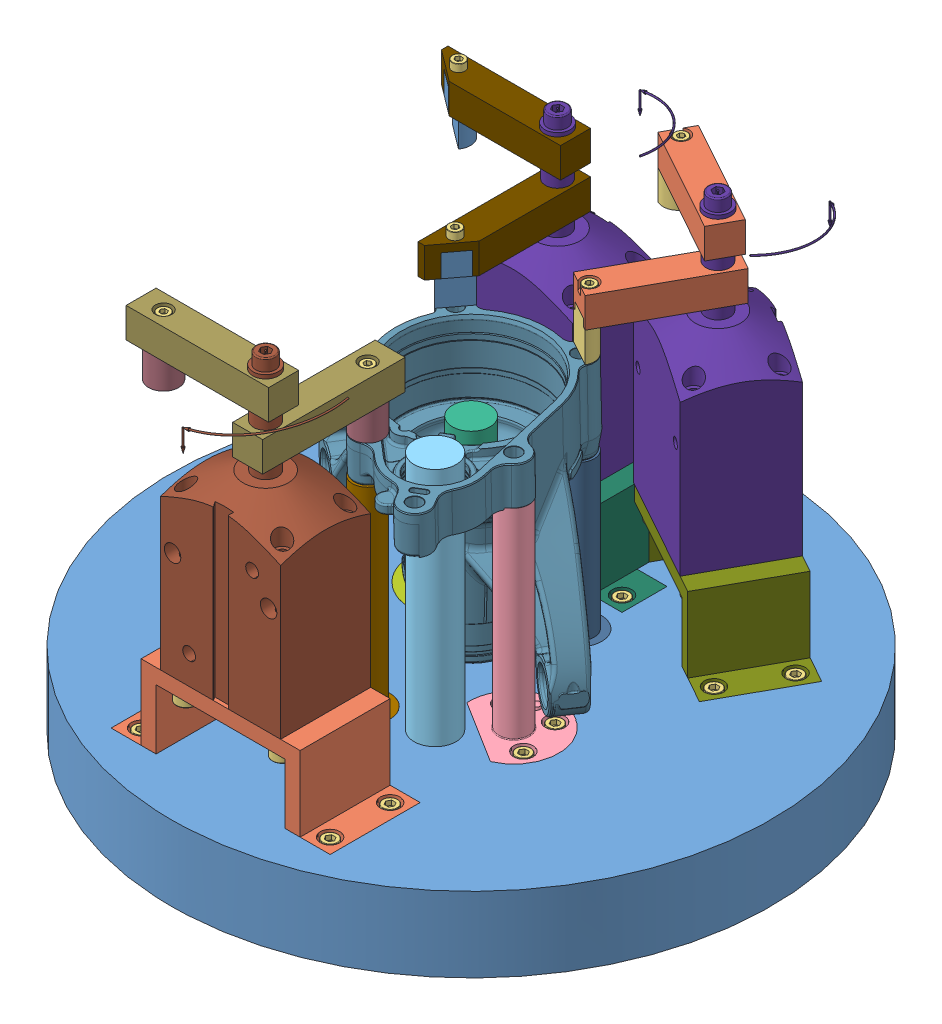
SolidWorks assembly assemb_base_31, configuration Default. Lengths in mm.
Overall size (400 290.01 400).
77 component instances, 24 part files, 96 mates.
Components (placement in the parent):
- Base_31-1: Base_31 [Default] at (159.0315 190.3727 314.3837) size (400 50 400)
- apoio_clamping_body-1: apoio_clamping_body [Default] at (159.1438 280.3727 451.4976) size (146 65 60)
- socket head cap screw_iso-1: socket head cap screw_iso [ISO 4762 M6 x 16 - 16N] at (222.1438 239.7727 431.4976) x (0 -1 0) z (0 0 1) size (22 10 10)
- socket head cap screw_iso-2: socket head cap screw_iso [ISO 4762 M6 x 16 - 16N] at (222.1438 239.7727 471.4976) x (0 -1 0) z (0 0 1) size (22 10 10)
- socket head cap screw_iso-3: socket head cap screw_iso [ISO 4762 M6 x 16 - 16N] at (96.1438 239.7727 471.4976) x (0 -1 0) z (0 0 1) size (22 10 10)
- socket head cap screw_iso-4: socket head cap screw_iso [ISO 4762 M6 x 16 - 16N] at (96.1438 239.7727 431.4976) x (0 -1 0) z (0 0 1) size (22 10 10)
- assemb_pino_posi_t1-1: assemb_pino_posi_t1 [Default] at (344.3368 218.4069 358.9702) x (-0.529295 0 0.848438) z (-0.848438 0 -0.529295) size (47 161.34 60)
  - suporte_posi_t1-1: suporte_posi_t1 [Default] at (55.5939 6.9658 111.8626) size (47 149 60)
  - pino_t1-1: pino_t1 [Default] at (55.5939 58.9658 111.8626) x (0 0 1) z (-1 0 0) size (14.5 109 14.5)
  - mola_posicionamento-1: mola_posicionamento [Default] at (55.5939 58.9658 111.8626) x (-0.837169 0 -0.546944) z (-0.546944 0 0.837169) size (14.66 52.36 14.64)
- assemb_pino_posi_t2-1: assemb_pino_posi_t2 [Default] at (29.2532 222.3882 331.9322) x (0 0 -1) z (1 0 0) size (60 130.34 60)
  - suporte_posi_t2-1: suporte_posi_t2 [Default] at (49.445 2.9845 87.4507) size (60 118 60)
  - pino_t2-1: pino_t2 [Default] at (49.445 54.9845 87.4507) size (14.5 78 14.5)
  - mola_posicionamento-1: mola_posicionamento [Default] at (49.445 54.9845 87.4507) x (-0.837169 0 -0.546944) z (-0.546944 0 0.837169) size (14.66 52.36 14.64)
- suporte_apoio_t1-1: suporte_apoio_t1 [Default] at (159.0315 225.3727 383.4976) x (0.932563 0 0.361008) z (-0.361008 0 0.932563) size (30 163.5 30)
- suporte_apoio_t2-1: suporte_apoio_t2 [Default] at (184.7261 225.3727 268.029) x (-0.000113 0 1) z (-1 0 -0.000113) size (30 133 30)
- socket head cap screw_iso-9: socket head cap screw_iso [ISO 4762 M6 x 16 - 16N] at (230.5886 239.7727 329.9611) x (0 -1 0) z (0 0 1) size (22 10 10)
- socket head cap screw_iso-11: socket head cap screw_iso [ISO 4762 M6 x 16 - 16N] at (203.0339 239.7727 336.344) x (0 -1 0) z (0 0 1) size (22 10 10)
- socket head cap screw_iso-12: socket head cap screw_iso [ISO 4762 M6 x 16 - 16N] at (136.7038 239.7727 282.4872) x (0 -1 0) z (0 0 1) size (22 10 10)
- socket head cap screw_iso-13: socket head cap screw_iso [ISO 4762 M6 x 16 - 16N] at (116.7038 239.7727 302.4872) x (0 -1 0) z (0 0 1) size (22 10 10)
- socket head cap screw_iso-14: socket head cap screw_iso [ISO 4762 M6 x 16 - 16N] at (116.7038 239.7727 262.4872) x (0 -1 0) z (0 0 1) size (22 10 10)
- socket head cap screw_iso-15: socket head cap screw_iso [ISO 4762 M6 x 16 - 16N] at (96.7038 239.7727 282.4872) x (0 -1 0) z (0 0 1) size (22 10 10)
- assemb_pneu_clamp_v3-1: assemb_pneu_clamp_v3 [Default] at (226.4561 301.3275 626.5786) x (-1 0 0) z (0 0 -1) size (138.53 190.01 139)
  - clamping_body_cw-1: clamping_body_cw [Default] at (67.3123 178.5452 175.0811) x (-1 0 0) z (0 1 0) size (95.58 86.05 190.01)
  - assemb_braco_v3-1: assemb_braco_v3 [Default] at (78.3965 110.7532 94.4609) size (95 40 21.92)
    - clamping_arm_sp_v3-1: clamping_arm_sp_v3 [Default] at (-11.0842 57.292 80.6201) x (1 0 0) z (0 1 0) size (95 20 20)
    - contact_end_full-1: contact_end_full [Default] at (56.9158 17.292 80.6201) x (0.994886 0 -0.101006) z (0.101006 0 0.994886) size (20 25 20)
    - socket head cap screw_iso-2: socket head cap screw_iso [ISO 4762 M5 x 16 - 16N] at (56.9158 56.292 80.6201) x (0 -1 0) z (0 0 1) size (21 8.5 8.5)
  - assemb_braco_v3-2: assemb_braco_v3 [Default] at (147.9324 80.7532 186.1653) x (0 0 1) z (-1 0 0) size (95 40 21.92)
    - clamping_arm_sp_v3-1: clamping_arm_sp_v3 [Default] at (-11.0842 57.292 80.6201) x (1 0 0) z (0 1 0) size (95 20 20)
    - contact_end_full-1: contact_end_full [Default] at (56.9158 17.292 80.6201) x (0.994886 0 -0.101006) z (0.101006 0 0.994886) size (20 25 20)
    - socket head cap screw_iso-2: socket head cap screw_iso [ISO 4762 M5 x 16 - 16N] at (56.9158 56.292 80.6201) x (0 -1 0) z (0 0 1) size (21 8.5 8.5)
- socket head cap screw_iso-24: socket head cap screw_iso [ISO 4762 M8 x 12 - 12N] at (191.1438 272.3727 430.4976) x (0 1 0) z (0 0 1) size (28 13 13)
- socket head cap screw_iso-25: socket head cap screw_iso [ISO 4762 M8 x 12 - 12N] at (191.1438 272.3727 472.4976) x (0 1 0) z (0 0 1) size (28 13 13)
- socket head cap screw_iso-26: socket head cap screw_iso [ISO 4762 M8 x 12 - 12N] at (127.1438 272.3727 430.4976) x (0 1 0) z (0 0 1) size (28 13 13)
- socket head cap screw_iso-27: socket head cap screw_iso [ISO 4762 M8 x 12 - 12N] at (127.1438 272.3727 472.4976) x (0 1 0) z (0 0 1) size (28 13 13)
- Peça_Cliente-1: Peça_Cliente [Default] at (159.0315 399.3727 314.3837) x (0.857167 0 -0.515038) z (0 -1 0) size (175.56 233.49 149.01)
- apoio_clamping_body_cut1-1: apoio_clamping_body_cut1 [Default] at (116.7038 280.3727 214.4872) size (146 65 60)
- apoio_clamping_body_cut2-1: apoio_clamping_body_cut2 [Default] at (217.693 280.3727 208.5548) x (0.874621 0 0.484807) z (-0.484807 0 0.874621) size (146 65 60)
- assemb_pneu_clamp_v2-2: assemb_pneu_clamp_v2 [Default] at (61.4178 300.0224 42.113) size (138.53 190.01 139)
  - clamping_body_ccw-1: clamping_body_ccw [Default] at (55.286 179.8503 172.3742) x (-1 0 0) z (0 1 0) size (95.58 86.05 190.01)
  - assemb_braco_v2-1: assemb_braco_v2 [Default] at (45.4961 98.2616 242.6188) x (-1 0 0) z (0 0 -1) size (95 45 24)
    - clamping_arm_sp_v2-1: clamping_arm_sp_v2 [Default] at (-9.7899 71.0887 70.2446) x (1 0 0) z (0 1 0) size (95 20 20)
    - contact_end_spec-1: contact_end_spec [Default] at (58.2101 31.0887 70.2446) x (0.601815 0 -0.798636) z (0.798636 0 0.601815) size (14.5 35 20)
    - socket head cap screw_iso-1: socket head cap screw_iso [ISO 4762 M5 x 12 - 12N] at (57.3074 76.0887 71.4426) x (0 -1 0) z (0 0 1) size (17 8.5 8.5)
  - assemb_braco_v2-2: assemb_braco_v2 [Default] at (125.5306 68.2616 182.1641) x (0 0 1) z (-1 0 0) size (95 45 24)
    - clamping_arm_sp_v2-1: clamping_arm_sp_v2 [Default] at (-9.7899 71.0887 70.2446) x (1 0 0) z (0 1 0) size (95 20 20)
    - contact_end_spec-1: contact_end_spec [Default] at (58.2101 31.0887 70.2446) x (0.601815 0 -0.798636) z (0.798636 0 0.601815) size (14.5 35 20)
    - socket head cap screw_iso-1: socket head cap screw_iso [ISO 4762 M5 x 12 - 12N] at (57.3074 76.0887 71.4426) x (0 -1 0) z (0 0 1) size (17 8.5 8.5)
- assemb_pneu_clamp_v1-2: assemb_pneu_clamp_v1 [Default] at (249.1962 287.189 38.6259) x (0.874621 0 0.484807) z (-0.484807 0 0.874621) size (123.53 190.01 124)
  - clamping_body_ccw-1: clamping_body_ccw [Default] at (54.8293 192.6837 163.8964) x (-1 0 0) z (0 1 0) size (95.58 86.05 190.01)
  - assemb_braco_v1-1: assemb_braco_v1 [Default] at (54.1161 128.0797 225.0616) x (-1 0 0) z (0 0 -1) size (80 40 20)
    - clamping_arm_sp_v1-2: clamping_arm_sp_v1 [Default] at (-0.7132 54.1041 61.1653) x (1 0 0) z (0 1 0) size (80 20 20)
    - contact_end_half-1: contact_end_half [Default] at (67.2868 14.1041 61.1653) size (10 25 20)
    - socket head cap screw_iso-2: socket head cap screw_iso [ISO 4762 M5 x 16 - 16N] at (62.2868 53.6041 61.1653) x (0 -1 0) z (0 0 1) size (21 8.5 8.5)
  - assemb_braco_v1-2: assemb_braco_v1 [Default] at (115.9945 98.0797 164.6096) x (0 0 1) z (-1 0 0) size (80 40 20)
    - clamping_arm_sp_v1-2: clamping_arm_sp_v1 [Default] at (-0.7132 54.1041 61.1653) x (1 0 0) z (0 1 0) size (80 20 20)
    - contact_end_half-1: contact_end_half [Default] at (67.2868 14.1041 61.1653) size (10 25 20)
    - socket head cap screw_iso-2: socket head cap screw_iso [ISO 4762 M5 x 16 - 16N] at (62.2868 53.6041 61.1653) x (0 -1 0) z (0 0 1) size (21 8.5 8.5)
- socket head cap screw_iso-36: socket head cap screw_iso [ISO 4762 M6 x 16 - 16N] at (263.098 239.7727 256.59) x (0 -1 0) z (0 0 1) size (22 10 10)
- socket head cap screw_iso-37: socket head cap screw_iso [ISO 4762 M6 x 16 - 16N] at (282.4903 239.7727 221.6052) x (0 -1 0) z (0 0 1) size (22 10 10)
- socket head cap screw_iso-38: socket head cap screw_iso [ISO 4762 M6 x 16 - 16N] at (172.288 239.7727 160.5195) x (0 -1 0) z (0 0 1) size (22 10 10)
- socket head cap screw_iso-39: socket head cap screw_iso [ISO 4762 M6 x 16 - 16N] at (53.7038 239.7727 194.4872) x (0 -1 0) z (0 0 1) size (22 10 10)
- socket head cap screw_iso-40: socket head cap screw_iso [ISO 4762 M6 x 16 - 16N] at (53.7038 239.7727 234.4872) x (0 -1 0) z (0 0 1) size (22 10 10)
- socket head cap screw_iso-41: socket head cap screw_iso [ISO 4762 M6 x 16 - 16N] at (179.7038 239.7727 234.4872) x (0 -1 0) z (0 0 1) size (22 10 10)
- socket head cap screw_iso-42: socket head cap screw_iso [ISO 4762 M8 x 12 - 12N] at (84.7038 272.3727 235.4872) x (0 1 0) z (0 0 1) size (28 13 13)
- socket head cap screw_iso-43: socket head cap screw_iso [ISO 4762 M8 x 20 - 20N] at (84.7038 272.3727 193.4872) x (0 1 0) z (0 0 1) size (28 13 13)
- socket head cap screw_iso-44: socket head cap screw_iso [ISO 4762 M8 x 12 - 12N] at (148.7038 272.3727 193.4872) x (0 1 0) z (0 0 1) size (28 13 13)
- socket head cap screw_iso-45: socket head cap screw_iso [ISO 4762 M8 x 12 - 12N] at (148.7038 272.3727 235.4872) x (0 1 0) z (0 0 1) size (28 13 13)
- socket head cap screw_iso-46: socket head cap screw_iso [ISO 4762 M8 x 12 - 12N] at (179.5242 272.3727 211.408) x (0 1 0) z (0 0 1) size (28 13 13)
- socket head cap screw_iso-47: socket head cap screw_iso [ISO 4762 M8 x 12 - 12N] at (199.886 272.3727 174.6739) x (0 1 0) z (0 0 1) size (28 13 13)
- socket head cap screw_iso-48: socket head cap screw_iso [ISO 4762 M8 x 12 - 12N] at (255.8618 272.3727 205.7015) x (0 1 0) z (0 0 1) size (28 13 13)
- socket head cap screw_iso-49: socket head cap screw_iso [ISO 4762 M8 x 12 - 12N] at (235.4999 272.3727 242.4356) x (0 1 0) z (0 0 1) size (28 13 13)
- socket head cap screw_iso-50: socket head cap screw_iso [ISO 4762 M6 x 16 - 16N] at (236.9715 239.7727 357.5158) x (0 -1 0) z (0 0 1) size (22 10 10)
- parallel pin hardened 02_iso-1: parallel pin hardened 02_iso [ISO 8735-6x28-A-St] at (215.4893 242.4727 327.4458) x (0 -1 0) z (0 0 1) size (28 6 6)
- pino_guia_t1-1: pino_guia_t1 [Default] at (195.0205 240.3727 374.3899) x (0.986605 0 -0.163126) z (0.163126 0 0.986605) size (28 180 28)
- pino_guia_t2-1: pino_guia_t2 [Default] at (159.0167 240.3727 314.3589) x (0.978415 0 0.206649) z (-0.206649 0 0.978415) size (25 153 25)
Mates (geometry in assembly coordinates):
- Concentric5: concentric aligned: cylinder of Base_31-1 through (222.1438 225.3727 471.4976) axis (0 1 0) radius 2.5; cylinder of apoio_clamping_body-1 through (222.1438 225.3727 471.4976) axis (0 1 0) radius 3.3
- Concentric6: concentric aligned: cylinder of Base_31-1 through (96.1438 225.3727 431.4976) axis (0 1 0) radius 2.5; cylinder of apoio_clamping_body-1 through (96.1438 225.3727 431.4976) axis (0 1 0) radius 3.3
- Coincident3: coincident anti-aligned: plane of Base_31-1 through (159.0315 225.3727 314.3837) normal (0 1 0); plane of apoio_clamping_body-1 through (159.1438 225.3727 451.4976) normal (0 -1 0)
- Concentric7: concentric aligned: cylinder of apoio_clamping_body-1 through (222.1438 225.3727 431.4976) axis (0 1 0) radius 3.3; cylinder of socket head cap screw_iso-1 through (222.1438 271.5227 431.4976) axis (0 1 0) radius 5
- Coincident4: coincident anti-aligned: plane of apoio_clamping_body-1 through (222.1438 233.7727 431.4976) normal (0 1 0); plane of socket head cap screw_iso-1 through (227.1438 233.7727 431.4976) normal (0 -1 0)
- Concentric8: concentric aligned: cylinder of apoio_clamping_body-1 through (222.1438 225.3727 471.4976) axis (0 1 0) radius 3.3; cylinder of socket head cap screw_iso-2 through (222.1438 271.5227 471.4976) axis (0 1 0) radius 5
- Coincident5: coincident anti-aligned: plane of apoio_clamping_body-1 through (222.1438 233.7727 471.4976) normal (0 1 0); plane of socket head cap screw_iso-2 through (227.1438 233.7727 471.4976) normal (0 -1 0)
- Concentric9: concentric aligned: cylinder of apoio_clamping_body-1 through (96.1438 225.3727 471.4976) axis (0 1 0) radius 3.3; cylinder of socket head cap screw_iso-3 through (96.1438 271.5227 471.4976) axis (0 1 0) radius 5
- Coincident6: coincident anti-aligned: plane of apoio_clamping_body-1 through (96.1438 233.7727 471.4976) normal (0 1 0); plane of socket head cap screw_iso-3 through (101.1438 233.7727 471.4976) normal (0 -1 0)
- Concentric10: concentric aligned: cylinder of apoio_clamping_body-1 through (96.1438 225.3727 431.4976) axis (0 1 0) radius 3.3; cylinder of socket head cap screw_iso-4 through (96.1438 271.5227 431.4976) axis (0 1 0) radius 5
- Coincident7: coincident anti-aligned: plane of apoio_clamping_body-1 through (96.1438 233.7727 431.4976) normal (0 1 0); plane of socket head cap screw_iso-4 through (101.1438 233.7727 431.4976) normal (0 -1 0)
- Concentric15: concentric aligned: cylinder of Base_31-1 through (203.0339 225.3727 336.344) axis (0 1 0) radius 2.5; cylinder of assemb_pino_posi_t1-1/suporte_posi_t1-1 through (203.0339 225.3727 336.344) axis (0 1 0) radius 3.2
- Coincident12: coincident anti-aligned: plane of Base_31-1 through (220.0027 225.3727 346.9299) normal (0 1 0); plane of assemb_pino_posi_t1-1/suporte_posi_t1-1 through (220.0027 225.3727 346.9299) normal (0 -1 0)
- Concentric17: concentric anti-aligned: cylinder of Base_31-1 through (116.7038 225.3727 282.4872) axis (0 1 0) radius 30; cylinder of assemb_pino_posi_t2-1/suporte_posi_t2-1 through (116.7038 240.3727 282.4872) axis (0 -1 0) radius 30
- Concentric18: concentric aligned: cylinder of Base_31-1 through (136.7038 225.3727 282.4872) axis (0 1 0) radius 2.5; cylinder of assemb_pino_posi_t2-1/suporte_posi_t2-1 through (136.7038 225.3727 282.4872) axis (0 1 0) radius 3.2
- Coincident13: coincident anti-aligned: plane of Base_31-1 through (116.7038 225.3727 282.4872) normal (0 1 0); plane of assemb_pino_posi_t2-1/suporte_posi_t2-1 through (116.7038 225.3727 282.4872) normal (0 -1 0)
- Concentric19: concentric anti-aligned: cylinder of Base_31-1 through (159.0315 225.3727 383.4976) axis (0 1 0) radius 15; cylinder of suporte_apoio_t1-1 through (159.0315 240.3727 383.4976) axis (0 -1 0) radius 15
- Coincident14: coincident anti-aligned: plane of Base_31-1 through (159.0315 225.3727 383.4976) normal (0 1 0); plane of suporte_apoio_t1-1 through (159.0315 225.3727 383.4976) normal (0 -1 0)
- Concentric20: concentric anti-aligned: cylinder of Base_31-1 through (184.7261 225.3727 268.029) axis (0 1 0) radius 15; cylinder of suporte_apoio_t2-1 through (184.7261 240.3727 268.029) axis (0 -1 0) radius 15
- Coincident15: coincident anti-aligned: plane of Base_31-1 through (184.7261 225.3727 268.029) normal (0 1 0); plane of suporte_apoio_t2-1 through (184.7261 225.3727 268.029) normal (0 -1 0)
- Concentric21: concentric aligned: cylinder of assemb_pino_posi_t1-1/suporte_posi_t1-1 through (230.5886 225.3727 329.9611) axis (0 1 0) radius 3.2; cylinder of socket head cap screw_iso-9 through (230.5886 271.5227 329.9611) axis (0 1 0) radius 5
- Coincident16: coincident anti-aligned: plane of assemb_pino_posi_t1-1/suporte_posi_t1-1 through (230.5886 233.7727 329.9611) normal (0 1 0); plane of socket head cap screw_iso-9 through (235.5886 233.7727 329.9611) normal (0 -1 0)
- Concentric23: concentric aligned: cylinder of assemb_pino_posi_t1-1/suporte_posi_t1-1 through (203.0339 225.3727 336.344) axis (0 1 0) radius 3.2; cylinder of socket head cap screw_iso-11 through (203.0339 271.5227 336.344) axis (0 1 0) radius 5
- Coincident18: coincident anti-aligned: plane of assemb_pino_posi_t1-1/suporte_posi_t1-1 through (203.0339 233.7727 336.344) normal (0 1 0); plane of socket head cap screw_iso-11 through (208.0339 233.7727 336.344) normal (0 -1 0)
- Concentric24: concentric aligned: cylinder of assemb_pino_posi_t2-1/suporte_posi_t2-1 through (136.7038 225.3727 282.4872) axis (0 1 0) radius 3.2; cylinder of socket head cap screw_iso-12 through (136.7038 271.5227 282.4872) axis (0 1 0) radius 5
- Coincident19: coincident anti-aligned: plane of assemb_pino_posi_t2-1/suporte_posi_t2-1 through (136.7038 233.7727 282.4872) normal (0 1 0); plane of socket head cap screw_iso-12 through (141.7038 233.7727 282.4872) normal (0 -1 0)
- Concentric25: concentric aligned: cylinder of assemb_pino_posi_t2-1/suporte_posi_t2-1 through (116.7038 225.3727 302.4872) axis (0 1 0) radius 3.2; cylinder of socket head cap screw_iso-13 through (116.7038 271.5227 302.4872) axis (0 1 0) radius 5
- Coincident20: coincident anti-aligned: plane of assemb_pino_posi_t2-1/suporte_posi_t2-1 through (116.7038 233.7727 302.4872) normal (0 1 0); plane of socket head cap screw_iso-13 through (121.7038 233.7727 302.4872) normal (0 -1 0)
- Concentric26: concentric aligned: cylinder of assemb_pino_posi_t2-1/suporte_posi_t2-1 through (116.7038 225.3727 262.4872) axis (0 1 0) radius 3.2; cylinder of socket head cap screw_iso-14 through (116.7038 271.5227 262.4872) axis (0 1 0) radius 5
- Coincident21: coincident anti-aligned: plane of assemb_pino_posi_t2-1/suporte_posi_t2-1 through (116.7038 233.7727 262.4872) normal (0 1 0); plane of socket head cap screw_iso-14 through (121.7038 233.7727 262.4872) normal (0 -1 0)
- Concentric27: concentric aligned: cylinder of assemb_pino_posi_t2-1/suporte_posi_t2-1 through (96.7038 225.3727 282.4872) axis (0 1 0) radius 3.2; cylinder of socket head cap screw_iso-15 through (96.7038 271.5227 282.4872) axis (0 1 0) radius 5
- Coincident22: coincident anti-aligned: plane of assemb_pino_posi_t2-1/suporte_posi_t2-1 through (96.7038 233.7727 282.4872) normal (0 1 0); plane of socket head cap screw_iso-15 through (101.7038 233.7727 282.4872) normal (0 -1 0)
- Coincident23: coincident aligned: plane of apoio_clamping_body-1 through (106.1438 290.3727 421.4976) normal (0 0 -1); plane of assemb_pneu_clamp_v3-1/clamping_body_cw-1 through (119.1438 410.8727 421.4976) normal (0 0 -1)
- Concentric28: concentric aligned: cylinder of apoio_clamping_body-1 through (191.1438 225.3727 430.4976) axis (0 1 0) radius 4.5; cylinder of assemb_pneu_clamp_v3-1/clamping_body_cw-1 through (191.1438 290.3727 430.4976) axis (0 1 0) radius 3.375
- Concentric29: concentric aligned: cylinder of apoio_clamping_body-1 through (127.1438 225.3727 472.4976) axis (0 1 0) radius 4.5; cylinder of assemb_pneu_clamp_v3-1/clamping_body_cw-1 through (127.1438 290.3727 472.4976) axis (0 1 0) radius 3.375
- Coincident25: coincident anti-aligned: plane of apoio_clamping_body-1 through (159.1438 290.3727 451.4976) normal (0 1 0); plane of assemb_pneu_clamp_v3-1/clamping_body_cw-1 through (199.1438 290.3727 481.4976) normal (0 -1 0)
- Concentric42: concentric anti-aligned: cylinder of apoio_clamping_body-1 through (191.1438 225.3727 430.4976) axis (0 1 0) radius 4.5; cylinder of socket head cap screw_iso-24 through (191.1438 240.6227 430.4976) axis (0 -1 0) radius 6.5
- Coincident36: coincident anti-aligned: plane of apoio_clamping_body-1 through (159.1438 280.3727 451.4976) normal (0 -1 0); plane of socket head cap screw_iso-24 through (184.6438 280.3727 430.4976) normal (0 1 0)
- Concentric43: concentric anti-aligned: cylinder of apoio_clamping_body-1 through (191.1438 225.3727 472.4976) axis (0 1 0) radius 4.5; cylinder of socket head cap screw_iso-25 through (191.1438 240.6227 472.4976) axis (0 -1 0) radius 6.5
- Coincident37: coincident anti-aligned: plane of apoio_clamping_body-1 through (159.1438 280.3727 451.4976) normal (0 -1 0); plane of socket head cap screw_iso-25 through (184.6438 280.3727 472.4976) normal (0 1 0)
- Concentric44: concentric anti-aligned: cylinder of apoio_clamping_body-1 through (127.1438 225.3727 430.4976) axis (0 1 0) radius 4.5; cylinder of socket head cap screw_iso-26 through (127.1438 240.6227 430.4976) axis (0 -1 0) radius 6.5
- Coincident38: coincident anti-aligned: plane of apoio_clamping_body-1 through (159.1438 280.3727 451.4976) normal (0 -1 0); plane of socket head cap screw_iso-26 through (120.6438 280.3727 430.4976) normal (0 1 0)
- Concentric45: concentric anti-aligned: cylinder of apoio_clamping_body-1 through (127.1438 225.3727 472.4976) axis (0 1 0) radius 4.5; cylinder of socket head cap screw_iso-27 through (127.1438 240.6227 472.4976) axis (0 -1 0) radius 6.5
- Coincident39: coincident anti-aligned: plane of apoio_clamping_body-1 through (159.1438 280.3727 451.4976) normal (0 -1 0); plane of socket head cap screw_iso-27 through (120.6438 280.3727 472.4976) normal (0 1 0)
- Concentric46: concentric aligned: cylinder of assemb_pino_posi_t1-1/pino_t1-1 through (220.0027 386.3727 346.9299) axis (0 1 0) radius 5; cylinder of Peça_Cliente-1 through (220.0027 369.6714 346.9299) axis (0 1 0) radius 4.75
- Concentric47: concentric aligned: cylinder of Peça_Cliente-1 through (116.7038 337.4784 282.4872) axis (0 1 0) radius 4.5; cylinder of assemb_pino_posi_t2-1/pino_t2-1 through (116.7038 355.3727 282.4872) axis (0 1 0) radius 5
- Coincident40: coincident anti-aligned: plane of assemb_pino_posi_t1-1/suporte_posi_t1-1 through (220.0027 374.3727 346.9299) normal (0 1 0); plane of Peça_Cliente-1 through (220.0027 374.3727 346.9299) normal (0 -1 0)
- Concentric48: concentric aligned: cylinder of Base_31-1 through (53.7038 225.3727 194.4872) axis (0 1 0) radius 2.5; cylinder of apoio_clamping_body_cut1-1 through (53.7038 225.3727 194.4872) axis (0 1 0) radius 3.3
- Concentric49: concentric aligned: cylinder of Base_31-1 through (179.7038 225.3727 234.4872) axis (0 1 0) radius 2.5; cylinder of apoio_clamping_body_cut1-1 through (179.7038 225.3727 234.4872) axis (0 1 0) radius 3.3
- Coincident41: coincident anti-aligned: plane of Base_31-1 through (159.0315 225.3727 314.3837) normal (0 1 0); plane of apoio_clamping_body_cut1-1 through (116.7038 225.3727 214.4872) normal (0 -1 0)
- Concentric50: concentric aligned: cylinder of Base_31-1 through (263.098 225.3727 256.59) axis (0 1 0) radius 2.5; cylinder of apoio_clamping_body_cut2-1 through (263.098 225.3727 256.59) axis (0 1 0) radius 3.3
- Concentric51: concentric aligned: cylinder of Base_31-1 through (172.288 225.3727 160.5195) axis (0 1 0) radius 2.5; cylinder of apoio_clamping_body_cut2-1 through (172.288 225.3727 160.5195) axis (0 1 0) radius 3.3
- Coincident42: coincident anti-aligned: plane of Base_31-1 through (159.0315 225.3727 314.3837) normal (0 1 0); plane of apoio_clamping_body_cut2-1 through (217.693 225.3727 208.5548) normal (0 -1 0)
- Coincident43: coincident aligned: plane of apoio_clamping_body_cut1-1 through (63.7038 290.3727 244.4872) normal (0 0 1); plane of assemb_pneu_clamp_v2-2/clamping_body_ccw-1 through (156.7038 410.8727 244.4872) normal (0 0 1)
- Concentric52: concentric aligned: cylinder of apoio_clamping_body_cut1-1 through (148.7038 225.3727 235.4872) axis (0 1 0) radius 4.5; cylinder of assemb_pneu_clamp_v2-2/clamping_body_ccw-1 through (148.7038 290.3727 235.4872) axis (0 1 0) radius 3.25
- Coincident44: coincident anti-aligned: plane of apoio_clamping_body_cut1-1 through (116.7038 290.3727 214.4872) normal (0 1 0); plane of assemb_pneu_clamp_v2-2/clamping_body_ccw-1 through (76.7038 290.3727 184.4872) normal (0 -1 0)
- Coincident45: coincident aligned: plane of apoio_clamping_body_cut2-1 through (156.7938 290.3727 209.0987) normal (-0.484807 0 0.874621); plane of assemb_pneu_clamp_v1-2/clamping_body_ccw-1 through (238.1336 410.8727 254.1857) normal (-0.484807 0 0.874621)
- Concentric53: concentric aligned: cylinder of apoio_clamping_body_cut2-1 through (235.4999 225.3727 242.4356) axis (0 1 0) radius 4.5; cylinder of assemb_pneu_clamp_v1-2/clamping_body_ccw-1 through (235.4999 290.3727 242.4356) axis (0 1 0) radius 3.25
- Coincident46: coincident anti-aligned: plane of apoio_clamping_body_cut2-1 through (217.693 290.3727 208.5548) normal (0 1 0); plane of assemb_pneu_clamp_v1-2/clamping_body_ccw-1 through (197.2523 290.3727 162.9239) normal (0 -1 0)
- Concentric62: concentric aligned: cylinder of apoio_clamping_body_cut2-1 through (263.098 225.3727 256.59) axis (0 1 0) radius 3.3; cylinder of socket head cap screw_iso-36 through (263.098 271.5227 256.59) axis (0 1 0) radius 5
- Coincident54: coincident anti-aligned: plane of apoio_clamping_body_cut2-1 through (263.098 233.7727 256.59) normal (0 1 0); plane of socket head cap screw_iso-36 through (268.098 233.7727 256.59) normal (0 -1 0)
- Concentric63: concentric aligned: cylinder of apoio_clamping_body_cut2-1 through (282.4903 225.3727 221.6052) axis (0 1 0) radius 3.3; cylinder of socket head cap screw_iso-37 through (282.4903 271.5227 221.6052) axis (0 1 0) radius 5
- Coincident55: coincident anti-aligned: plane of apoio_clamping_body_cut2-1 through (282.4903 233.7727 221.6052) normal (0 1 0); plane of socket head cap screw_iso-37 through (287.4903 233.7727 221.6052) normal (0 -1 0)
- Concentric64: concentric aligned: cylinder of apoio_clamping_body_cut2-1 through (172.288 225.3727 160.5195) axis (0 1 0) radius 3.3; cylinder of socket head cap screw_iso-38 through (172.288 271.5227 160.5195) axis (0 1 0) radius 5
- Coincident56: coincident anti-aligned: plane of apoio_clamping_body_cut2-1 through (172.288 233.7727 160.5195) normal (0 1 0); plane of socket head cap screw_iso-38 through (177.288 233.7727 160.5195) normal (0 -1 0)
- Concentric65: concentric aligned: cylinder of apoio_clamping_body_cut1-1 through (53.7038 225.3727 194.4872) axis (0 1 0) radius 3.3; cylinder of socket head cap screw_iso-39 through (53.7038 271.5227 194.4872) axis (0 1 0) radius 5
- Coincident57: coincident anti-aligned: plane of apoio_clamping_body_cut1-1 through (53.7038 233.7727 194.4872) normal (0 1 0); plane of socket head cap screw_iso-39 through (58.7038 233.7727 194.4872) normal (0 -1 0)
- Concentric66: concentric aligned: cylinder of apoio_clamping_body_cut1-1 through (53.7038 225.3727 234.4872) axis (0 1 0) radius 3.3; cylinder of socket head cap screw_iso-40 through (53.7038 271.5227 234.4872) axis (0 1 0) radius 5
- Coincident58: coincident anti-aligned: plane of apoio_clamping_body_cut1-1 through (53.7038 233.7727 234.4872) normal (0 1 0); plane of socket head cap screw_iso-40 through (58.7038 233.7727 234.4872) normal (0 -1 0)
- Concentric67: concentric aligned: cylinder of apoio_clamping_body_cut1-1 through (179.7038 225.3727 234.4872) axis (0 1 0) radius 3.3; cylinder of socket head cap screw_iso-41 through (179.7038 271.5227 234.4872) axis (0 1 0) radius 5
- Coincident59: coincident anti-aligned: plane of apoio_clamping_body_cut1-1 through (179.7038 233.7727 234.4872) normal (0 1 0); plane of socket head cap screw_iso-41 through (184.7038 233.7727 234.4872) normal (0 -1 0)
- Concentric68: concentric anti-aligned: cylinder of apoio_clamping_body_cut1-1 through (84.7038 225.3727 235.4872) axis (0 1 0) radius 4.5; cylinder of socket head cap screw_iso-42 through (84.7038 240.6227 235.4872) axis (0 -1 0) radius 6.5
- Coincident60: coincident anti-aligned: plane of apoio_clamping_body_cut1-1 through (116.7038 280.3727 214.4872) normal (0 -1 0); plane of socket head cap screw_iso-42 through (78.2038 280.3727 235.4872) normal (0 1 0)
- Concentric69: concentric anti-aligned: cylinder of apoio_clamping_body_cut1-1 through (84.7038 225.3727 193.4872) axis (0 1 0) radius 4.5; cylinder of socket head cap screw_iso-43 through (84.7038 240.6227 193.4872) axis (0 -1 0) radius 6.5
- Coincident61: coincident anti-aligned: plane of apoio_clamping_body_cut1-1 through (116.7038 280.3727 214.4872) normal (0 -1 0); plane of socket head cap screw_iso-43 through (78.2038 280.3727 193.4872) normal (0 1 0)
- Concentric70: concentric anti-aligned: cylinder of apoio_clamping_body_cut1-1 through (148.7038 225.3727 193.4872) axis (0 1 0) radius 4.5; cylinder of socket head cap screw_iso-44 through (148.7038 240.6227 193.4872) axis (0 -1 0) radius 6.5
- Coincident62: coincident anti-aligned: plane of apoio_clamping_body_cut1-1 through (116.7038 280.3727 214.4872) normal (0 -1 0); plane of socket head cap screw_iso-44 through (142.2038 280.3727 193.4872) normal (0 1 0)
- Concentric71: concentric anti-aligned: cylinder of apoio_clamping_body_cut1-1 through (148.7038 225.3727 235.4872) axis (0 1 0) radius 4.5; cylinder of socket head cap screw_iso-45 through (148.7038 240.6227 235.4872) axis (0 -1 0) radius 6.5
- Coincident63: coincident anti-aligned: plane of apoio_clamping_body_cut1-1 through (116.7038 280.3727 214.4872) normal (0 -1 0); plane of socket head cap screw_iso-45 through (142.2038 280.3727 235.4872) normal (0 1 0)
- Concentric72: concentric anti-aligned: cylinder of apoio_clamping_body_cut2-1 through (179.5242 225.3727 211.408) axis (0 1 0) radius 4.5; cylinder of socket head cap screw_iso-46 through (179.5242 240.6227 211.408) axis (0 -1 0) radius 6.5
- Coincident64: coincident anti-aligned: plane of apoio_clamping_body_cut2-1 through (217.693 280.3727 208.5548) normal (0 -1 0); plane of socket head cap screw_iso-46 through (173.0242 280.3727 211.408) normal (0 1 0)
- Concentric73: concentric anti-aligned: cylinder of apoio_clamping_body_cut2-1 through (199.886 225.3727 174.6739) axis (0 1 0) radius 4.5; cylinder of socket head cap screw_iso-47 through (199.886 240.6227 174.6739) axis (0 -1 0) radius 6.5
- Coincident65: coincident anti-aligned: plane of apoio_clamping_body_cut2-1 through (217.693 280.3727 208.5548) normal (0 -1 0); plane of socket head cap screw_iso-47 through (193.386 280.3727 174.6739) normal (0 1 0)
- Concentric74: concentric anti-aligned: cylinder of apoio_clamping_body_cut2-1 through (255.8618 225.3727 205.7015) axis (0 1 0) radius 4.5; cylinder of socket head cap screw_iso-48 through (255.8618 240.6227 205.7015) axis (0 -1 0) radius 6.5
- Coincident66: coincident anti-aligned: plane of apoio_clamping_body_cut2-1 through (217.693 280.3727 208.5548) normal (0 -1 0); plane of socket head cap screw_iso-48 through (249.3618 280.3727 205.7015) normal (0 1 0)
- Concentric75: concentric anti-aligned: cylinder of apoio_clamping_body_cut2-1 through (235.4999 225.3727 242.4356) axis (0 1 0) radius 4.5; cylinder of socket head cap screw_iso-49 through (235.4999 240.6227 242.4356) axis (0 -1 0) radius 6.5
- Coincident67: coincident anti-aligned: plane of apoio_clamping_body_cut2-1 through (217.693 280.3727 208.5548) normal (0 -1 0); plane of socket head cap screw_iso-49 through (228.9999 280.3727 242.4356) normal (0 1 0)
- Concentric76: concentric anti-aligned: circle of Base_31-1; cylinder of assemb_pino_posi_t1-1/suporte_posi_t1-1 through (220.0027 374.3727 346.9299) axis (0 -1 0) radius 10
- Concentric77: concentric aligned: cylinder of assemb_pino_posi_t1-1/suporte_posi_t1-1 through (236.9715 225.3727 357.5158) axis (0 1 0) radius 3.2; cylinder of socket head cap screw_iso-50 through (236.9715 271.5227 357.5158) axis (0 1 0) radius 5
- Coincident68: coincident anti-aligned: plane of assemb_pino_posi_t1-1/suporte_posi_t1-1 through (236.9715 233.7727 357.5158) normal (0 1 0); plane of socket head cap screw_iso-50 through (241.9715 233.7727 357.5158) normal (0 -1 0)
- Concentric78: concentric aligned: cylinder of assemb_pino_posi_t1-1/suporte_posi_t1-1 through (215.4893 225.3727 327.4458) axis (0 1 0) radius 3; cylinder of parallel pin hardened 03_iso-1 through (215.4893 252.4727 327.4458) axis (0 1 0) radius 3
- Tangent1: tangent anti-aligned: circle of parallel pin hardened 02_iso-1; circle of assemb_pino_posi_t1-1/suporte_posi_t1-1
- Concentric79: concentric aligned: circle of Base_31-1; cylinder of pino_guia_t2-1 through (159.0167 220.3727 314.3589) axis (0 1 0) radius 6
- Coincident69: coincident anti-aligned: plane of Base_31-1 through (159.0315 240.3727 314.3837) normal (0 1 0); plane of pino_guia_t2-1 through (159.0167 240.3727 314.3589) normal (0 -1 0)
- Concentric80: concentric aligned: cylinder of Base_31-1 through (195.0205 240.3727 374.3899) axis (0 1 0) radius 5.25; cylinder of pino_guia_t1-1 through (195.0205 220.3727 374.3899) axis (0 1 0) radius 6
- Coincident70: coincident anti-aligned: plane of Base_31-1 through (159.0315 240.3727 314.3837) normal (0 1 0); plane of pino_guia_t1-1 through (195.0205 240.3727 374.3899) normal (0 -1 0)
